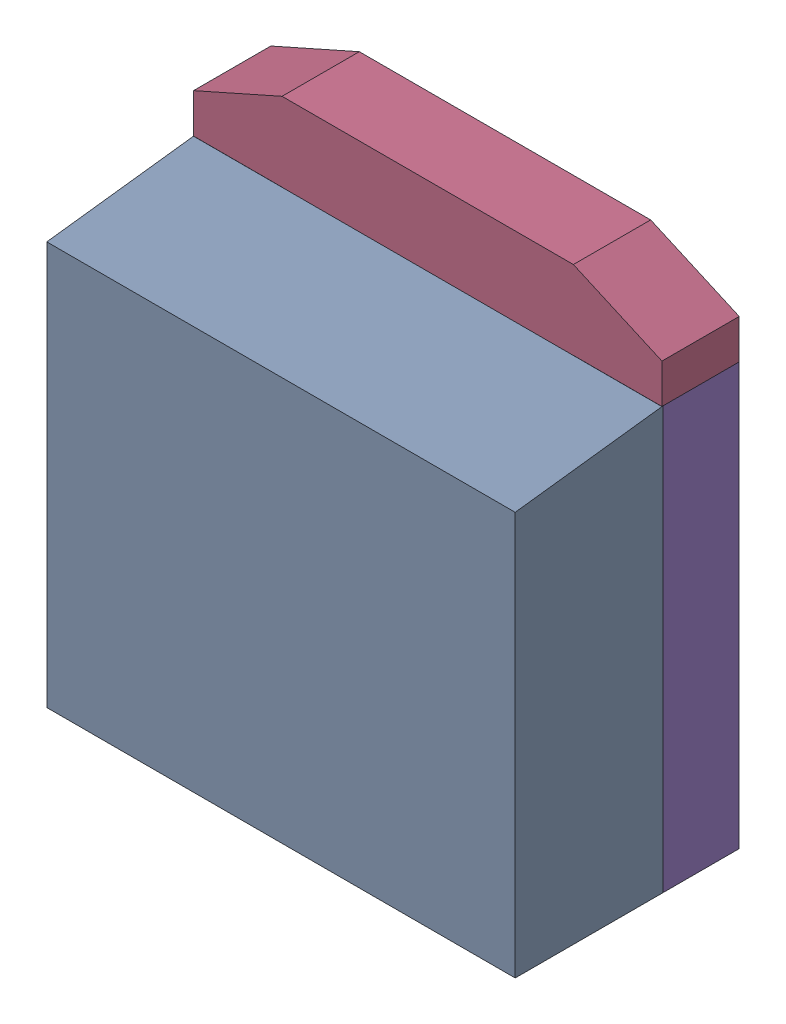
SolidWorks assembly SW3dPS-TO263-3S_BODY3, configuration Default. Lengths in mm.
Overall size (10 10.68 4.78).
14 component instances, 6 part files, 0 mates.
Components (placement in the parent):
- SW3dPS-TO263-3S_Free-Models7-1: SW3dPS-TO263-3S_Free-Models7 [Default] at origin size (10 10.68 4.78)
  - SW3dPS-TO263-3S_BODY4-1: SW3dPS-TO263-3S_BODY4 [Default] at (0.0127 0 1.5827) x (0 0 1) z (-1 0 0) size (3.15 9 10)
    - SW3dPS-TO263-3S_Free-Models8-1: SW3dPS-TO263-3S_Free-Models8 [Default] at origin size (3.15 9 10)
      - SW3dPS-TO263-3S_453496017-1: SW3dPS-TO263-3S_453496017 [Default] at (0 4.4 -4.9873) size (3.15 9 10)
        - SW3dPS-TO263-3S_Extruded18-1: SW3dPS-TO263-3S_Extruded18 [Default] at origin size (3.15 9 10)
    - SW3dPS-TO263-3S_Board7-1: SW3dPS-TO263-3S_Board7 [Default] at (0 0 -0.0938) size (0.01 0.01 0.11)
  - SW3dPS-TO263-3S_BODY5-1: SW3dPS-TO263-3S_BODY5 [Default] at (0 0 0.0127) size (10 10.68 1.65)
    - SW3dPS-TO263-3S_Board6-1: SW3dPS-TO263-3S_Board6 [Default] at (0 0 -0.0938) size (0.01 0.01 0.11)
    - SW3dPS-TO263-3S_Free-Models9-1: SW3dPS-TO263-3S_Free-Models9 [Default] at origin size (10 10.68 1.65)
      - SW3dPS-TO263-3S_453494353-1: SW3dPS-TO263-3S_453494353 [Default] at (0 7.15 -1.6373) size (10 6.86 1.65)
        - SW3dPS-TO263-3S_Extruded15-1: SW3dPS-TO263-3S_Extruded15 [Default] at origin size (10 6.86 1.65)
      - SW3dPS-TO263-3S_453494225-1: SW3dPS-TO263-3S_453494225 [Default] at (0 4.4 -1.6373) size (10 9 1.65)
        - SW3dPS-TO263-3S_Extruded17-1: SW3dPS-TO263-3S_Extruded17 [Default] at origin size (10 9 1.65)
- SW3dPS-TO263-3S_Board8-1: SW3dPS-TO263-3S_Board8 [Default] at (0 0 -0.0938) size (0.01 0.01 0.11)
